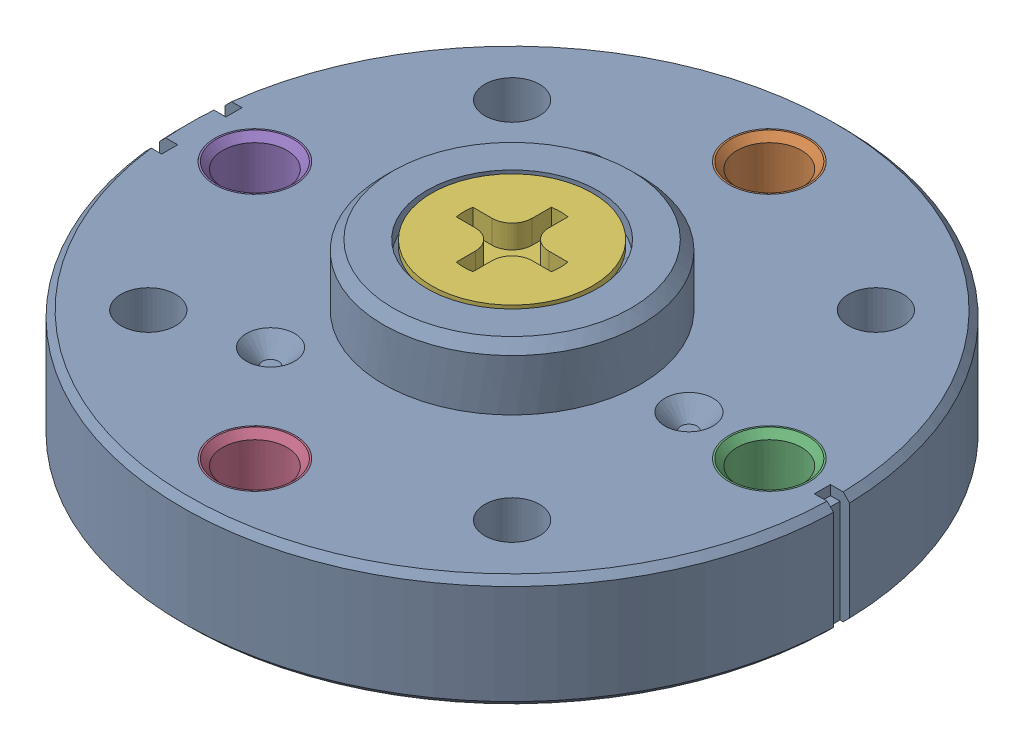
SolidWorks assembly M_DC11_A01_HORN_ASM, configuration Default. Lengths in mm.
Overall size (20.5 6 20.5).
6 component instances, 3 part files, 0 mates.
Components (placement in the parent):
- M_DC11_A01_HORN_1-1: M_DC11_A01_HORN_1 [Default] at origin size (20.5 5.4 20.5)
- DC11_A01_HORN_INSERT_1-1: DC11_A01_HORN_INSERT_1 [Default] at (0 3.5 -8) x (-1 0 0) z (0 0 1) size (2.97 3.5 2.97)
- DC11_A01_HORN_INSERT_1-2: DC11_A01_HORN_INSERT_1 [Default] at (8 3.5 0) x (-1 0 0) z (0 0 1) size (2.97 3.5 2.97)
- DC11_A01_HORN_INSERT_1-3: DC11_A01_HORN_INSERT_1 [Default] at (0 3.5 8) x (-1 0 0) z (0 0 1) size (2.97 3.5 2.97)
- DC11_A01_HORN_INSERT_1-4: DC11_A01_HORN_INSERT_1 [Default] at (-8 3.5 0) x (-1 0 0) z (0 0 1) size (2.97 3.5 2.97)
- FHS_M2_5X06_NYLOK_1-1: FHS_M2_5X06_NYLOK_1 [Default] at (0 3.95 0) size (5 6 5)
